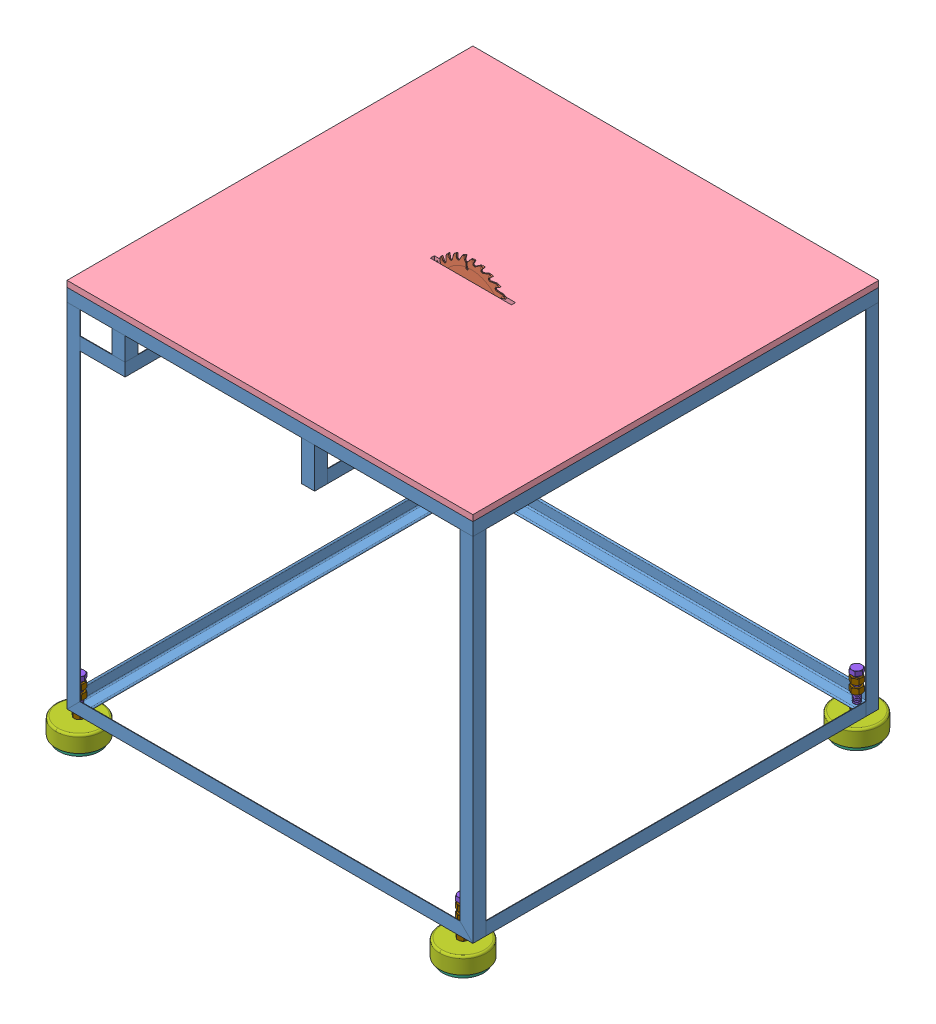
SolidWorks assembly Serra circular montagem, configuration Valor predeterminado. Lengths in mm.
Overall size (1060.89 1187.64 1085).
102 component instances, 29 part files, 47 mates.
Components (placement in the parent):
- Estrutura serra circular-1: Estrutura serra circular [Valor predeterminado<Como usinado>] at (-638.2464 -415.5425 500) size (1000 1122.09 1000)
- Serra circular de bancada-1: Serra circular de bancada [Default] at (-81.841 461.4233 50.7774) x (0.990198 0.139667 0) z (0 0 -1) size (508.56 311.6 431.24)
  - cirsaw-1: cirsaw [Default] at (-60.7832 8.4139 49.2774) size (202.41 202.41 3.87)
  - Eixo Serra Circular 5-8 N1-1: Eixo Serra Circular 5-8 N1 [Valor predeterminado] at (-60.7832 8.4139 212.2774) x (0 0 -1) z (-1 0 0) size (431.24 80.12 104.06)
    - Base Principal-1: Base Principal [Valor predeterminado] at origin size (240 75.12 104.06)
    - Eixo Principal-1: Eixo Principal [Valor predeterminado] at (9 0 0) size (431.24 28 28)
    - Tampa Rolamento-1: Tampa Rolamento [Valor predeterminado] at (121.5 0 0) x (0 0 1) z (-1 0 0) size (62 62 3)
    - Tampa Rolamento-2: Tampa Rolamento [Valor predeterminado] at (-121.5 0 0) x (0 0 1) z (1 0 0) size (62 62 3)
    - Suporte Principal-1: Suporte Principal [Valor predeterminado] at (152 0 0) size (16 67.5 67.5)
    - Suporte Principal-2: Suporte Principal [Valor predeterminado] at (171 0 0) x (-1 0 0) z (0 0 -1) size (16 67.5 67.5)
    - Polia Correa Dupla-1: Polia Correa Dupla [Valor predeterminado] at (-157 0 0) size (50 75 75)
    - angular contact ball bearing_68_skf_SKF - 7204 BE - 10,DE,AC,10_68-1: angular contact ball bearing_68_skf_SKF - 7204 BE - 10,DE,AC,10_68 [Valor predeterminado] at (113 0 0) size (14 47 47)
    - angular contact ball bearing_68_skf_SKF - 7204 BE - 10,DE,AC,10_68-2: angular contact ball bearing_68_skf_SKF - 7204 BE - 10,DE,AC,10_68 [Valor predeterminado] at (-113 0 0) size (14 47 47)
    - spring pin slotted_hd_din_Spring Pin ISO 8752 - 6 x 50 - N - St-1: spring pin slotted_hd_din_Spring Pin ISO 8752 - 6 x 50 - N - St [Valor predeterminado] at (-176 0 25) x (0 0 -1) z (0 -1 0) size (50 6 5.99)
    - socket head cap screw_am_B18.3.1M - 6 x 1.0 x 16 Hex SHCS -- 16SHX-1: socket head cap screw_am_B18.3.1M - 6 x 1.0 x 16 Hex SHCS -- 16SHX [Valor predeterminado] at (127 24.2487 -14) x (-1 0 0) z (0 0.924225 0.381849) size (22 10 10)
    - socket head cap screw_am_B18.3.1M - 6 x 1.0 x 16 Hex SHCS -- 16SHX-2: socket head cap screw_am_B18.3.1M - 6 x 1.0 x 16 Hex SHCS -- 16SHX [Valor predeterminado] at (127 0 28) x (-1 0 0) z (0 0.924225 0.381849) size (22 10 10)
    - socket head cap screw_am_B18.3.1M - 6 x 1.0 x 16 Hex SHCS -- 16SHX-3: socket head cap screw_am_B18.3.1M - 6 x 1.0 x 16 Hex SHCS -- 16SHX [Valor predeterminado] at (127 -24.2487 -14) x (-1 0 0) z (0 0.924225 0.381849) size (22 10 10)
    - socket head cap screw_am_B18.3.1M - 6 x 1.0 x 16 Hex SHCS -- 16SHX-4: socket head cap screw_am_B18.3.1M - 6 x 1.0 x 16 Hex SHCS -- 16SHX [Valor predeterminado] at (-127 24.2487 -14) size (22 10 10)
    - socket head cap screw_am_B18.3.1M - 6 x 1.0 x 16 Hex SHCS -- 16SHX-5: socket head cap screw_am_B18.3.1M - 6 x 1.0 x 16 Hex SHCS -- 16SHX [Valor predeterminado] at (-127 0 28) size (22 10 10)
    - socket head cap screw_am_B18.3.1M - 6 x 1.0 x 16 Hex SHCS -- 16SHX-6: socket head cap screw_am_B18.3.1M - 6 x 1.0 x 16 Hex SHCS -- 16SHX [Valor predeterminado] at (-127 -24.2487 -14) size (22 10 10)
    - hex nut heavy_am_B18.2.4.6M - Heavy hex nut,  M16 x 2 --D-S-1: hex nut heavy_am_B18.2.4.6M - Heavy hex nut,  M16 x 2 --D-S [Valor predeterminado] at (179 0 0) x (0 1 0) z (-1 0 0) size (27 31.18 17.1)
  - Motor IEC  W21_GENERAL_PURPOSE  03_FRAME_80  WITH_FLANG-1: Motor IEC  W21_GENERAL_PURPOSE  03_FRAME_80  WITH_FLANG [Valor predeterminado] at (-332.4526 135.6764 223.2774) x (0 0 1) z (-1 0 0) size (300.91 163.14 218.82)
  - Polia Correa Dupla-1: Polia Correa Dupla [Valor predeterminado] at (-332.4526 135.6764 352.2774) x (0 0 1) z (0 1 0) size (50 75 75)
  - Correia-1: Correia [Predeterminada] at (-196.6179 72.0451 368.2774) x (0.905565 -0.424208 0) z (0 0 1) size (375 75 12)
  - Correia-3: Correia [Predeterminada] at (-196.6179 72.0451 353.2774) x (0.905565 -0.424208 0) z (0 0 1) size (375 75 12)
  - Base motor e eixo-1: Base motor e eixo [Predeterminada] at (-208.7832 55.6764 212.2774) x (-1 0 0) z (0 -1 0) size (430 200 4.76)
  - Esticador do motor-1: Esticador do motor [Predeterminada] at (-234.2582 65.2014 223.7774) size (19.05 19.05 127)
  - Gonzo fêmea-1: Gonzo fêmea [Valor predeterminado] at (-423.7832 44.5639 127.2774) x (1 0 0) z (0 0 -1) size (26.35 12.7 30)
  - Gonzo fêmea-3: Gonzo fêmea [Valor predeterminado] at (-423.7832 44.5639 297.2774) x (1 0 0) z (0 0 -1) size (26.35 12.7 30)
  - parafuso sextavado din 931-1 - m8 x 50-1: parafuso sextavado din 931-1 - m8 x 50 [Valor predeterminado] at (-207.9526 65.2014 273.7774) x (-1 0 0) z (0 0.832935 -0.553371) size (55.3 15.01 13)
  - parafuso sextavado din 931-1 - m8 x 50-3: parafuso sextavado din 931-1 - m8 x 50 [Valor predeterminado] at (-207.9526 65.2014 173.7774) x (-1 0 0) z (0 0.832935 -0.553371) size (55.3 15.01 13)
  - porca sextavada din 555-5 - m8-1: porca sextavada din 555-5 - m8 [Valor predeterminado] at (-224.7332 65.2014 173.7774) size (6.64 15.01 13)
  - porca sextavada din 555-5 - m8-3: porca sextavada din 555-5 - m8 [Valor predeterminado] at (-224.7332 65.2014 273.7774) size (6.64 15.01 13)
  - parafuso sextavado din 931-1 - m10 x 40-1: parafuso sextavado din 931-1 - m10 x 40 [Valor predeterminado] at (-269.9526 68.6764 173.2774) x (0 -1 0) z (0.546944 0 -0.837169) size (46.4 19.63 17)
  - arruela lisa din 125 - a 10,5-1: arruela lisa din 125 - a 10,5 [Valor predeterminado] at (-269.9526 50.9139 173.2774) x (0 -1 0) z (0 0 1) size (2 20 20)
  - porca sextavada din 555-5 - m10-1: porca sextavada din 555-5 - m10 [Valor predeterminado] at (-269.9526 48.9139 173.2774) x (0 -1 0) z (0 0 1) size (8 19.63 17)
  - parafuso sextavado din 931-1 - m10 x 40-3: parafuso sextavado din 931-1 - m10 x 40 [Valor predeterminado] at (-269.9526 68.6764 273.2774) x (0 -1 0) z (0.546944 0 -0.837169) size (46.4 19.63 17)
  - parafuso sextavado din 931-1 - m10 x 40-5: parafuso sextavado din 931-1 - m10 x 40 [Valor predeterminado] at (-394.9526 68.6764 173.2774) x (0 -1 0) z (0.983409 0 -0.181404) size (46.4 19.63 17)
  - parafuso sextavado din 931-1 - m10 x 40-7: parafuso sextavado din 931-1 - m10 x 40 [Valor predeterminado] at (-394.9526 68.6764 273.2774) x (0 -1 0) z (0.546944 0 -0.837169) size (46.4 19.63 17)
  - porca sextavada din 555-5 - m10-3: porca sextavada din 555-5 - m10 [Valor predeterminado] at (-394.9526 48.9139 173.2774) x (0 -1 0) z (0 0 1) size (8 19.63 17)
  - porca sextavada din 555-5 - m10-5: porca sextavada din 555-5 - m10 [Valor predeterminado] at (-269.9526 48.9139 273.2774) x (0 -1 0) z (-0.269704 0 0.962943) size (8 19.63 17)
  - porca sextavada din 555-5 - m10-7: porca sextavada din 555-5 - m10 [Valor predeterminado] at (-394.9526 48.9139 273.2774) x (0 -1 0) z (0 0 1) size (8 19.63 17)
  - arruela lisa din 125 - a 10,5-3: arruela lisa din 125 - a 10,5 [Valor predeterminado] at (-394.9526 50.9139 173.2774) x (0 -1 0) z (0 0 1) size (2 20 20)
  - arruela lisa din 125 - a 10,5-5: arruela lisa din 125 - a 10,5 [Valor predeterminado] at (-394.9526 50.9139 273.2774) x (0 -1 0) z (0 0 1) size (2 20 20)
  - arruela lisa din 125 - a 10,5-7: arruela lisa din 125 - a 10,5 [Valor predeterminado] at (-269.9526 50.9139 273.2774) x (0 -1 0) z (0 0 1) size (2 20 20)
  - Esticador do motor-3: Esticador do motor [Predeterminada] at (-133.3082 41.3889 212.2774) size (19.05 19.05 127)
  - parafuso sextavado din 931-1 - m8 x 50-5: parafuso sextavado din 931-1 - m8 x 50 [Valor predeterminado] at (-162.7832 41.3889 162.2774) x (1 0 0) z (0 -0.387923 0.921692) size (55.3 15.01 13)
  - porca sextavada din 555-5 - m8-5: porca sextavada din 555-5 - m8 [Valor predeterminado] at (-142.8332 41.3889 162.2774) x (-1 0 0) z (0 -0.924225 -0.381849) size (6.64 15.01 13)
  - porca sextavada din 555-5 - m8-7: porca sextavada din 555-5 - m8 [Valor predeterminado] at (-142.8332 41.3889 262.2774) x (-1 0 0) z (0 -0.924225 -0.381849) size (6.64 15.01 13)
  - parafuso sextavado din 931-1 - m8 x 50-7: parafuso sextavado din 931-1 - m8 x 50 [Valor predeterminado] at (-162.7832 41.3889 262.2774) x (1 0 0) z (0 -0.387923 0.921692) size (55.3 15.01 13)
  - parafuso sextavado din 931-1 - m10 x 40-9: parafuso sextavado din 931-1 - m10 x 40 [Valor predeterminado] at (-18.7832 37.9139 267.2774) x (0 1 0) z (-0.999339 0 0.03636) size (46.4 19.63 17)
  - parafuso sextavado din 931-1 - m10 x 40-11: parafuso sextavado din 931-1 - m10 x 40 [Valor predeterminado] at (-102.7832 37.9139 157.2774) x (0 1 0) z (0.414075 0 -0.910243) size (46.4 19.63 17)
  - parafuso sextavado din 931-1 - m10 x 40-13: parafuso sextavado din 931-1 - m10 x 40 [Valor predeterminado] at (-102.7832 37.9139 267.2774) x (0 1 0) z (-0.996636 0 0.08195) size (46.4 19.63 17)
  - parafuso sextavado din 931-1 - m10 x 40-15: parafuso sextavado din 931-1 - m10 x 40 [Valor predeterminado] at (-18.7832 37.9139 157.2774) x (0 1 0) z (-0.887169 0 0.461445) size (46.4 19.63 17)
  - porca sextavada din 555-5 - m10-9: porca sextavada din 555-5 - m10 [Valor predeterminado] at (-18.7832 57.6764 267.2774) x (0 1 0) z (0.300888 0 -0.95366) size (8 19.63 17)
  - porca sextavada din 555-5 - m10-11: porca sextavada din 555-5 - m10 [Valor predeterminado] at (-102.7832 57.6764 267.2774) x (0 1 0) z (0.300888 0 -0.95366) size (8 19.63 17)
  - porca sextavada din 555-5 - m10-13: porca sextavada din 555-5 - m10 [Valor predeterminado] at (-102.7832 57.6764 157.2774) x (0 1 0) z (0.300888 0 -0.95366) size (8 19.63 17)
  - porca sextavada din 555-5 - m10-15: porca sextavada din 555-5 - m10 [Valor predeterminado] at (-18.7832 57.6764 157.2774) x (0 1 0) z (0.300888 0 -0.95366) size (8 19.63 17)
  - arruela lisa din 125 - a 10,5-9: arruela lisa din 125 - a 10,5 [Valor predeterminado] at (-102.7832 57.6764 157.2774) x (0 -1 0) z (0 0 1) size (2 20 20)
  - arruela lisa din 125 - a 10,5-11: arruela lisa din 125 - a 10,5 [Valor predeterminado] at (-102.7832 57.6764 267.2774) x (0 -1 0) z (0 0 1) size (2 20 20)
  - arruela lisa din 125 - a 10,5-13: arruela lisa din 125 - a 10,5 [Valor predeterminado] at (-18.7832 57.6764 267.2774) x (0 -1 0) z (0 0 1) size (2 20 20)
  - arruela lisa din 125 - a 10,5-15: arruela lisa din 125 - a 10,5 [Valor predeterminado] at (-18.7832 57.6764 157.2774) x (0 -1 0) z (0 0 1) size (2 20 20)
- Base de madeira da serra-1: Base de madeira da serra [Valor predeterminado] at (-138.2464 484.4575 0) x (1 0 0) z (0 1 0) size (1000 1000 15)
- Gonzo macho-1: Gonzo macho [Valor predeterminado] at (-495.2464 358.1075 -276.5) x (-1 0 0) z (0 0 1) size (26.35 12.7 60)
- Gonzo macho-3: Gonzo macho [Valor predeterminado] at (-495.2464 358.1075 -46.5) x (0 1 0) z (0 0 -1) size (26.35 12.7 60)
- VibraStop-1: VibraStop [Valor predeterminado] at (316.8547 -458.903 -485) size (115 142.88 115)
  - Borracha-1: Borracha [Valor predeterminado] at (5.7886 -22.1881 0) size (100 45 100)
  - Tampa-1: Tampa [Valor predeterminado] at (5.7886 -10.8381 0) size (115 40 115)
  - HBOLT 0.6250-18x4x4-S-1: HBOLT 0.6250-18x4x4-S [Valor predeterminado] at (5.7886 120.6895 0) x (0 -1 0) z (0 0 1) size (112.88 27.22 23.57)
  - HNUT 0.6250-18-D-S-1: HNUT 0.6250-18-D-S [Valor predeterminado] at (5.7886 29.1619 0) x (-0.342194 0 -0.939629) z (0 -1 0) size (23.83 27.51 14.2)
  - HNUT 0.6250-18-D-S-2: HNUT 0.6250-18-D-S [Valor predeterminado] at (5.7886 69.6647 0) x (1 0 0) z (0 -1 0) size (23.83 27.51 14.2)
  - HNUT 0.6250-18-D-S-3: HNUT 0.6250-18-D-S [Valor predeterminado] at (5.7886 90.2133 0) x (1 0 0) z (0 -1 0) size (23.83 27.51 14.2)
- VibraStop-3: VibraStop [Valor predeterminado] at (316.8547 -458.903 485) size (115 142.88 115)
  - Borracha-1: Borracha [Valor predeterminado] at (5.7886 -22.1881 0) size (100 45 100)
  - Tampa-1: Tampa [Valor predeterminado] at (5.7886 -10.8381 0) size (115 40 115)
  - HBOLT 0.6250-18x4x4-S-1: HBOLT 0.6250-18x4x4-S [Valor predeterminado] at (5.7886 120.6895 0) x (0 -1 0) z (0 0 1) size (112.88 27.22 23.57)
  - HNUT 0.6250-18-D-S-1: HNUT 0.6250-18-D-S [Valor predeterminado] at (5.7886 29.1619 0) x (-0.342194 0 -0.939629) z (0 -1 0) size (23.83 27.51 14.2)
  - HNUT 0.6250-18-D-S-2: HNUT 0.6250-18-D-S [Valor predeterminado] at (5.7886 69.6647 0) x (1 0 0) z (0 -1 0) size (23.83 27.51 14.2)
  - HNUT 0.6250-18-D-S-3: HNUT 0.6250-18-D-S [Valor predeterminado] at (5.7886 90.2133 0) x (1 0 0) z (0 -1 0) size (23.83 27.51 14.2)
- VibraStop-5: VibraStop [Valor predeterminado] at (-629.035 -458.903 485) size (115 142.88 115)
  - Borracha-1: Borracha [Valor predeterminado] at (5.7886 -22.1881 0) size (100 45 100)
  - Tampa-1: Tampa [Valor predeterminado] at (5.7886 -10.8381 0) size (115 40 115)
  - HBOLT 0.6250-18x4x4-S-1: HBOLT 0.6250-18x4x4-S [Valor predeterminado] at (5.7886 120.6895 0) x (0 -1 0) z (0 0 1) size (112.88 27.22 23.57)
  - HNUT 0.6250-18-D-S-1: HNUT 0.6250-18-D-S [Valor predeterminado] at (5.7886 29.1619 0) x (-0.342194 0 -0.939629) z (0 -1 0) size (23.83 27.51 14.2)
  - HNUT 0.6250-18-D-S-2: HNUT 0.6250-18-D-S [Valor predeterminado] at (5.7886 69.6647 0) x (1 0 0) z (0 -1 0) size (23.83 27.51 14.2)
  - HNUT 0.6250-18-D-S-3: HNUT 0.6250-18-D-S [Valor predeterminado] at (5.7886 90.2133 0) x (1 0 0) z (0 -1 0) size (23.83 27.51 14.2)
- VibraStop-7: VibraStop [Valor predeterminado] at (-629.035 -458.903 -485) size (115 142.88 115)
  - Borracha-1: Borracha [Valor predeterminado] at (5.7886 -22.1881 0) size (100 45 100)
  - Tampa-1: Tampa [Valor predeterminado] at (5.7886 -10.8381 0) size (115 40 115)
  - HBOLT 0.6250-18x4x4-S-1: HBOLT 0.6250-18x4x4-S [Valor predeterminado] at (5.7886 120.6895 0) x (0 -1 0) z (0 0 1) size (112.88 27.22 23.57)
  - HNUT 0.6250-18-D-S-1: HNUT 0.6250-18-D-S [Valor predeterminado] at (5.7886 29.1619 0) x (-0.342194 0 -0.939629) z (0 -1 0) size (23.83 27.51 14.2)
  - HNUT 0.6250-18-D-S-2: HNUT 0.6250-18-D-S [Valor predeterminado] at (5.7886 69.6647 0) x (1 0 0) z (0 -1 0) size (23.83 27.51 14.2)
  - HNUT 0.6250-18-D-S-3: HNUT 0.6250-18-D-S [Valor predeterminado] at (5.7886 90.2133 0) x (1 0 0) z (0 -1 0) size (23.83 27.51 14.2)
- parafuso sextavado din 931-1 - m12 x 100-1: parafuso sextavado din 931-1 - m12 x 100 [Valor predeterminado] at (-33.1154 313.4344 -74.5) x (-0.422618 0.906308 0) z (-0.453154 -0.211309 -0.866025) size (107.5 21.94 19)
- porca din 555-5 - m12-1: porca din 555-5 - m12 [Valor predeterminado] at (-53.5265 357.2062 -248.5303) x (0.422618 -0.906308 0) z (0 0 1) size (10.03 21.94 19)
- porca din 555-5 - m12-3: porca din 555-5 - m12 [Valor predeterminado] at (-43.7324 336.2025 -248.5303) x (-0.422618 0.906308 0) z (0 0 1) size (10.03 21.94 19)
- porca din 555-5 - m12-5: porca din 555-5 - m12 [Valor predeterminado] at (-53.5265 357.2062 -74.5) x (0.422618 -0.906308 0) z (0 0 1) size (10.03 21.94 19)
- porca din 555-5 - m12-7: porca din 555-5 - m12 [Valor predeterminado] at (-43.7324 336.2025 -74.5) x (-0.422618 0.906308 0) z (0 0 1) size (10.03 21.94 19)
- parafuso sextavado din 931-1 - m12 x 100-3: parafuso sextavado din 931-1 - m12 x 100 [Valor predeterminado] at (-33.1154 313.4344 -248.5303) x (-0.422618 0.906308 0) z (0.906308 0.422618 0) size (107.5 21.94 19)
- parafuso sextavado din 931-1 - m12 x 100-5: parafuso sextavado din 931-1 - m12 x 100 [Valor predeterminado] at (-1.8282 384.3971 -161.5) x (-0.906308 -0.422618 0) z (-0.198957 0.426664 0.882255) size (107.5 21.94 19)
- porca din 555-5 - m12-9: porca din 555-5 - m12 [Valor predeterminado] at (-34.9954 368.931 -161.5) x (0.906308 0.422618 0) z (0 0 1) size (10.03 21.94 19)
- porca din 555-5 - m12-11: porca din 555-5 - m12 [Valor predeterminado] at (-46.936 363.363 -161.5) x (0.906308 0.422618 0) z (0 0 1) size (10.03 21.94 19)
Mates (geometry in assembly coordinates):
- Coincidente1: coincident aligned: plane of Estrutura serra circular-1 through (-638.2464 -415.5425 0) normal (0 0 -1); plane of Serra circular de bancada-1/cirsaw-1 through (-138.9537 436.4105 0) normal (0 0 -1)
- Coincidente2: coincident: plane of Estrutura serra circular-1 through (-138.2464 -415.5425 500) normal (1 0 0); line of Serra circular de bancada-1/Eixo Serra Circular 5-8 N1-1/Eixo Principal-1 through (-138.2464 435.1424 -56.5) axis (0 0 -1)
- Paralelo2: parallel: plane of Estrutura serra circular-1 through (361.7536 452.7075 -500) normal (0 0 -1); plane of Serra circular de bancada-1/Base motor e eixo-1 through (-60.8754 368.3756 -273.2899) normal (0 0 -1)
- Coincidente4: coincident anti-aligned: plane of Estrutura serra circular-1 through (-606.4964 484.4575 -500) normal (0 1 0); plane of Base de madeira da serra-1 through (-138.2464 484.4575 0) normal (0 -1 0)
- Coincidente5: coincident aligned: plane of Estrutura serra circular-1 through (361.7536 452.7075 -500) normal (0 0 -1); plane of Base de madeira da serra-1 through (361.7536 499.4575 -500) normal (0 0 -1)
- Coincidente6: coincident aligned: plane of Estrutura serra circular-1 through (-638.2464 452.7075 -500) normal (-1 0 0); plane of Base de madeira da serra-1 through (-638.2464 499.4575 500) normal (-1 0 0)
- Coincidente8: coincident anti-aligned: plane of Estrutura serra circular-1 through (-526.9964 364.4575 500) normal (0 -1 0); plane of Gonzo macho-1 through (-495.2464 364.4575 -291.5) normal (0 1 0)
- Distância2: distance = 238.5 mm anti-aligned: plane of Gonzo macho-1 through (-495.2464 358.1075 -261.5) normal (0 0 1); plane of Estrutura serra circular-1 through (-495.2464 396.2075 -500) normal (0 0 -1)
- Coincidente10: coincident anti-aligned: plane of Estrutura serra circular-1 through (-495.2464 396.2075 500) normal (1 0 0); plane of Gonzo macho-1
- Concêntrico1: concentric aligned: cylinder of Serra circular de bancada-1/Gonzo fêmea-3 through (-495.2464 358.1075 -231.5) axis (0 0 -1) radius 6.35; cylinder of Gonzo macho-1 through (-495.2464 358.1075 -261.5) axis (0 0 -1) radius 6.35
- Coincidente11: coincident anti-aligned: plane of Serra circular de bancada-1/Gonzo fêmea-1 through (-495.2464 358.1075 -61.5) normal (0 0 1); plane of Gonzo macho-3 through (-495.2464 358.1075 -61.5) normal (0 0 -1)
- Concêntrico2: concentric anti-aligned: cylinder of Serra circular de bancada-1/Gonzo fêmea-1 through (-495.2464 358.1075 -61.5) axis (0 0 -1) radius 6.35; cylinder of Gonzo macho-3 through (-495.2464 358.1075 -91.5) axis (0 0 1) radius 3.25
- Paralelo3: parallel anti-aligned: plane of Estrutura serra circular-1 through (-495.2464 396.2075 500) normal (1 0 0); plane of Gonzo macho-3 through (-501.5964 358.1075 -31.5) normal (-1 0 0)
- Coincidente12: coincident anti-aligned: plane of Estrutura serra circular-1 through (330.0036 -415.5425 -500) normal (0 -1 0); plane of VibraStop-1/HNUT 0.6250-18-D-S-1 through (307.1902 -415.5425 -492.2024) normal (0 1 0)
- Coincidente13: coincident aligned: plane of VibraStop-1/Borracha-1 through (272.0433 -481.0911 -535.6) normal (0 -1 0); plane of VibraStop-7/Borracha-1 through (-673.8464 -481.0911 -535.6) normal (0 -1 0)
- Coincidente14: coincident aligned: plane of VibraStop-5/Borracha-1 through (-673.8464 -481.0911 434.4) normal (0 -1 0); plane of VibraStop-7/Borracha-1 through (-673.8464 -481.0911 -535.6) normal (0 -1 0)
- Coincidente15: coincident aligned: plane of VibraStop-3/Borracha-1 through (272.0433 -481.0911 434.4) normal (0 -1 0); plane of VibraStop-5/Borracha-1 through (-673.8464 -481.0911 434.4) normal (0 -1 0)
- Distância3: distance = 15 mm anti-aligned: plane of VibraStop-1/Tampa-1 through (322.6433 -469.7411 -485) normal (0 0 1); plane of Estrutura serra circular-1 through (361.7536 -383.7925 -500) normal (0 0 -1)
- Coincidente17: coincident aligned: plane of VibraStop-1 through (316.8547 -458.903 -485) normal (0 0 1); plane of VibraStop-7/Tampa-1 through (-623.2464 -469.7411 -485) normal (0 0 1)
- Distância4: distance = 15 mm anti-aligned: plane of VibraStop-7/Tampa-1 through (-623.2464 -469.7411 -485) normal (1 0 0); plane of Estrutura serra circular-1 through (-638.2464 -383.7925 -500) normal (-1 0 0)
- Coincidente19: coincident aligned: plane of VibraStop-1/Tampa-1 through (322.6433 -469.7411 -485) normal (1 0 0); plane of VibraStop-3/Tampa-1 through (322.6433 -469.7411 485) normal (1 0 0)
- Distância5: distance = 15 mm aligned: plane of VibraStop-3/Tampa-1 through (322.6433 -469.7411 485) normal (0 0 1); plane of Estrutura serra circular-1 through (-638.2464 -383.7925 500) normal (0 0 1)
- Coincidente21: coincident aligned: plane of VibraStop-3/Tampa-1 through (322.6433 -469.7411 485) normal (0 0 1); plane of VibraStop-5/Tampa-1 through (-623.2464 -469.7411 485) normal (0 0 1)
- Coincidente22: coincident aligned: plane of VibraStop-5/Tampa-1 through (-623.2464 -469.7411 485) normal (1 0 0); plane of VibraStop-7/Tampa-1 through (-623.2464 -469.7411 -485) normal (1 0 0)
- Coincidente23: coincident anti-aligned: plane of Estrutura serra circular-1 through (-57.0216 341.0394 -50) normal (0.422618 -0.906308 0); plane of porca din 555-5 - m12-7 through (-47.9585 345.2656 -74.5) normal (-0.422618 0.906308 0)
- Distância6: distance = 15 mm aligned: plane of porca din 555-5 - m12-7 through (-38.7614 338.5205 -65) normal (0 0 1); plane of Estrutura serra circular-1 through (-59.9964 354.4575 -50) normal (0 0 1)
- Distância7: distance = 10 mm: plane of porca din 555-5 - m12-7; line of Estrutura serra circular-1 through (-57.0216 341.0394 -50) axis (0 0 -1)
- Concêntrico4: concentric aligned: cylinder of parafuso sextavado din 931-1 - m12 x 100-1 through (-49.7815 349.175 -74.5) axis (-0.422618 0.906308 0) radius 6; cylinder of porca din 555-5 - m12-7 through (-34.9816 317.4365 -74.5) axis (-0.422618 0.906308 0) radius 5.053
- Coincidente26: coincident: line of Serra circular de bancada-1/Base motor e eixo-1 through (-68.5371 412.3545 -61.5) axis (0 0 -1); plane of parafuso sextavado din 931-1 - m12 x 100-1 through (-74.9759 409.3521 -76) normal (-0.422618 0.906308 0)
- Distância8: distance = 38 mm aligned: plane of parafuso sextavado din 931-1 - m12 x 100-1 through (-31.8991 310.8259 -74.5) normal (0.422618 -0.906308 0); plane of Estrutura serra circular-1 through (-57.0216 341.0394 -50) normal (0.422618 -0.906308 0)
- Coincidente28: coincident aligned: plane of parafuso sextavado din 931-1 - m12 x 100-1 through (-10.6893 265.3414 -74.5) normal (0.422618 -0.906308 0); plane of parafuso sextavado din 931-1 - m12 x 100-3 through (-10.6893 265.3414 -248.5303) normal (0.422618 -0.906308 0)
- Paralelo4: parallel aligned: plane of Estrutura serra circular-1 through (-41.6645 383.2328 -50) normal (0.906308 0.422618 0); plane of parafuso sextavado din 931-1 - m12 x 100-1 through (-4.9954 275.6098 -69.0152) normal (0.906308 0.422618 0)
- Coincidente30: coincident aligned: plane of parafuso sextavado din 931-1 - m12 x 100-1 through (-22.2153 267.5801 -79.9848) normal (-0.906308 -0.422618 0); plane of parafuso sextavado din 931-1 - m12 x 100-3 through (-22.2153 267.5801 -254.0152) normal (-0.906308 -0.422618 0)
- Distância9: distance = 2 mm: line of parafuso sextavado din 931-1 - m12 x 100-3 through (-13.6054 271.5949 -259.5) axis (0.422618 -0.906308 0); plane of Serra circular de bancada-1/Base motor e eixo-1 through (-67.4481 402.0274 -261.5) normal (0 0 -1)
- Coincidente32: coincident anti-aligned: plane of Estrutura serra circular-1 through (-55.4859 345.2587 -50) normal (-0.422618 0.906308 0); plane of porca din 555-5 - m12-5 through (-49.3004 348.1431 -74.5) normal (0.422618 -0.906308 0)
- Concêntrico5: concentric anti-aligned: cylinder of parafuso sextavado din 931-1 - m12 x 100-1 through (-49.7815 349.175 -74.5) axis (-0.422618 0.906308 0) radius 6; cylinder of porca din 555-5 - m12-5 through (-62.2773 375.9722 -74.5) axis (0.422618 -0.906308 0) radius 5.053
- Coincidente33: coincident aligned: plane of porca din 555-5 - m12-3 through (-43.7324 336.2025 -248.5303) normal (0.422618 -0.906308 0); plane of porca din 555-5 - m12-7 through (-43.7324 336.2025 -74.5) normal (0.422618 -0.906308 0)
- Concêntrico6: concentric aligned: cylinder of porca din 555-5 - m12-3 through (-34.9816 317.4365 -248.5303) axis (-0.422618 0.906308 0) radius 5.053; cylinder of parafuso sextavado din 931-1 - m12 x 100-3 through (-49.7815 349.175 -248.5303) axis (-0.422618 0.906308 0) radius 6
- Coincidente34: coincident aligned: plane of porca din 555-5 - m12-1 through (-53.5265 357.2062 -248.5303) normal (-0.422618 0.906308 0); plane of porca din 555-5 - m12-5 through (-53.5265 357.2062 -74.5) normal (-0.422618 0.906308 0)
- Concêntrico7: concentric anti-aligned: cylinder of porca din 555-5 - m12-1 through (-62.2773 375.9722 -248.5303) axis (0.422618 -0.906308 0) radius 5.053; cylinder of parafuso sextavado din 931-1 - m12 x 100-3 through (-49.7815 349.175 -248.5303) axis (-0.422618 0.906308 0) radius 6
- Coincidente35: coincident anti-aligned: plane of Estrutura serra circular-1 through (-41.6645 383.2328 -50) normal (0.906308 0.422618 0); plane of porca din 555-5 - m12-9 through (-34.9954 368.931 -161.5) normal (-0.906308 -0.422618 0)
- Distância10: distance = 5 mm: plane of Estrutura serra circular-1 through (-57.0216 341.0394 -50) normal (0.422618 -0.906308 0); line of porca din 555-5 - m12-9 through (-28.9364 359.6527 -161.5) axis (0.906308 0.422618 0)
- Concêntrico8: concentric anti-aligned: cylinder of parafuso sextavado din 931-1 - m12 x 100-5 through (-87.1082 344.6304 -161.5) axis (-0.906308 -0.422618 0) radius 6; cylinder of porca din 555-5 - m12-9 through (-53.7614 360.1802 -161.5) axis (0.906308 0.422618 0) radius 5.053
- Coincidente37: coincident aligned: plane of Serra circular de bancada-1/Base motor e eixo-1; plane of porca din 555-5 - m12-9 through (-34.9954 368.931 -161.5) normal (0 0 1)
- Concêntrico9: concentric anti-aligned: cylinder of parafuso sextavado din 931-1 - m12 x 100-5 through (-87.1082 344.6304 -161.5) axis (-0.906308 -0.422618 0) radius 6; cylinder of porca din 555-5 - m12-11 through (-65.7021 354.6122 -161.5) axis (0.906308 0.422618 0) radius 5.053
- Coincidente38: coincident anti-aligned: plane of Estrutura serra circular-1 through (-43.2002 379.0135 -50) normal (-0.906308 -0.422618 0); plane of porca din 555-5 - m12-11 through (-37.8729 367.5891 -161.5) normal (0.906308 0.422618 0)
- Distância11: distance = 25 mm aligned: plane of parafuso sextavado din 931-1 - m12 x 100-5 through (-3.2746 383.7226 -161.5) normal (0.906308 0.422618 0); plane of porca din 555-5 - m12-9 through (-25.9323 373.1571 -161.5) normal (0.906308 0.422618 0)
